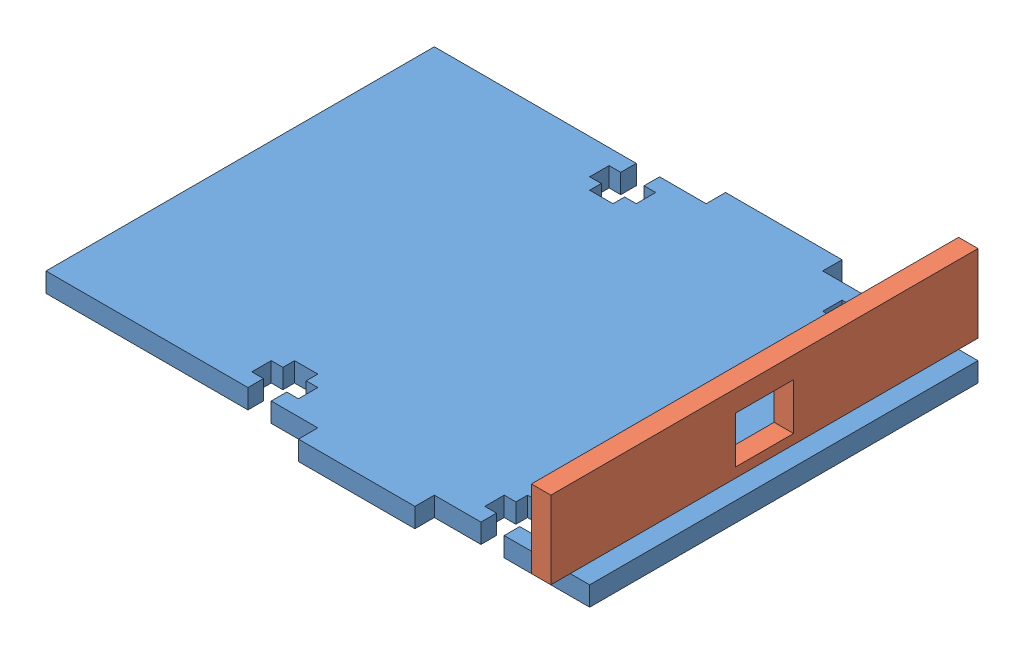
SolidWorks assembly Mount, configuration Default. Lengths in mm.
Overall size (88.9 15.88 73.03).
2 component instances, 2 part files, 3 mates.
Components (placement in the parent):
- phoneMount-1: phoneMount [Default] at (-6.5087 37.3881 95.3013) size (88.9 3.17 73.02)
- phoneMount2-1: phoneMount2 [Default] at (79.2163 40.5631 98.4763) x (0 1 0) z (0 0 1) size (15.88 3.18 73.03)
Mates (geometry in assembly coordinates):
- Coincident7: coincident aligned: plane of phoneMount-1 through (-6.5087 37.3881 95.3013) normal (0 -1 0); plane of phoneMount2-1 through (76.0413 37.3881 52.4388) normal (0 -1 0)
- Coincident8: coincident anti-aligned: plane of phoneMount-1 through (-6.5087 40.5631 52.4388) normal (0 0 1); plane of phoneMount2-1 through (76.0413 40.5631 52.4388) normal (0 0 -1)
- Coincident9: coincident anti-aligned: plane of phoneMount-1 through (76.0413 40.5631 95.3013) normal (1 0 0); plane of phoneMount2-1 through (76.0413 40.5631 98.4763) normal (-1 0 0)
